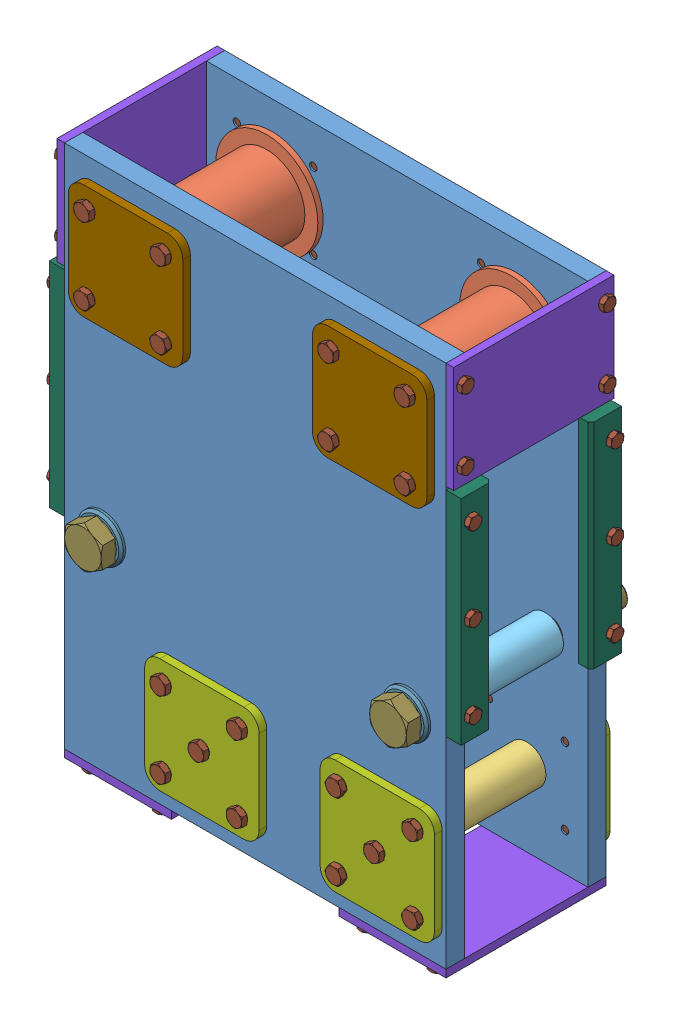
SolidWorks assembly 010200_trolley, configuration Default. Lengths in mm.
Overall size (277 352.5 150).
103 component instances, 15 part files, 231 mates.
Components (placement in the parent):
- 010201_trolley_main_plate-1: 010201_trolley_main_plate [Default] at (-125 -294 -52.5) size (250 344 12)
- 010201_trolley_main_plate-3: 010201_trolley_main_plate [Default] at (-125 -294 40.5) size (250 344 12)
- 010202_trolley_roller-1: 010202_trolley_roller [Default] at (-205 -50 0) size (67 67 105)
- 010202_trolley_roller-2: 010202_trolley_roller [Default] at (-45 -50 0) size (67 67 105)
- 010203_trolley_cylinder_pin-1: 010203_trolley_cylinder_pin [Default] at (-40 -294 0) size (25 25 105)
- 010203_trolley_cylinder_pin-3: 010203_trolley_cylinder_pin [Default] at (-155 -294 0) size (25 25 105)
- 010204_trolley_winch-1: 010204_trolley_winch [Default] at (-155 -294 0) x (0 0 1) z (0 1 0) size (30 100 100)
- 010205_trolley_small_roll-2: 010205_trolley_small_roll [Default] at (-25 -211 0) size (24 24 75)
- 010205_trolley_small_roll-3: 010205_trolley_small_roll [Default] at (-225 -211 0) size (24 24 75)
- 010207_trolley_distance_sleeve-2: 010207_trolley_distance_sleeve [Default] at (-155 -294 28) size (32 32 25)
- 010207_trolley_distance_sleeve-1: 010207_trolley_distance_sleeve [Default] at (-155 -294 -28) size (32 32 25)
- 010209_trolley_pincover-6: 010209_trolley_pincover [Default] at (-40 -294 -52.5) x (0 1 0) z (0 0 -1) size (75 75 5)
- 010209_trolley_pincover-7: 010209_trolley_pincover [Default] at (-155 -294 52.5) x (-1 0 0) z (0 0 1) size (75 75 5)
- 010209_trolley_pincover-8: 010209_trolley_pincover [Default] at (-155 -294 -52.5) x (1 0 0) z (0 0 -1) size (75 75 5)
- 010210_trolley_front_plate-4: 010210_trolley_front_plate [Default] at (-252.5 -35 0) x (0 0 1) z (-1 0 0) size (105 70 5)
- 010210_trolley_front_plate-8: 010210_trolley_front_plate [Default] at (2.5 -35 0) x (0 0 -1) z (1 0 0) size (105 70 5)
- 010210_trolley_front_plate-9: 010210_trolley_front_plate [Default] at (-35 -346.5 0) x (0 0 1) z (0 -1 0) size (105 70 5)
- 010210_trolley_front_plate-10: 010210_trolley_front_plate [Default] at (-215 -346.5 0) x (0 0 1) z (0 -1 0) size (105 70 5)
- 010208_trolley_bearing_cover-1: 010208_trolley_bearing_cover [Default] at (-205 -50 52.5) size (75 75 5)
- 010208_trolley_bearing_cover-7: 010208_trolley_bearing_cover [Default] at (-45 -50 52.5) size (75 75 5)
- 010208_trolley_bearing_cover-8: 010208_trolley_bearing_cover [Default] at (-45 -50 -52.5) x (-1 0 0) z (0 0 -1) size (75 75 5)
- 010208_trolley_bearing_cover-9: 010208_trolley_bearing_cover [Default] at (-205 -50 -52.5) x (-1 0 0) z (0 0 -1) size (75 75 5)
- SKF_6005_2z-1: SKF_6005_2z [Default] at (-45 -50 -52.5) size (47 47 12)
- SKF_6005_2z-2: SKF_6005_2z [Default] at (-205 -50 -52.5) size (47 47 12)
- SKF_6005_2z-3: SKF_6005_2z [Default] at (-205 -50 40.5) size (47 47 12)
- SKF_6005_2z-4: SKF_6005_2z [Default] at (-45 -50 40.5) size (47 47 12)
- 010209_trolley_pincover-9: 010209_trolley_pincover [Default] at (-40 -294 52.5) x (0 -1 0) z (0 0 1) size (75 75 5)
- hex screw gradeab_iso-78: hex screw gradeab_iso [ISO 4017 - M6 x 16-N] at (-40 -294 61.5) x (0 0 -1) z (1 0 0) size (20 11.55 10)
- hex screw gradeab_iso-79: hex screw gradeab_iso [ISO 4017 - M6 x 16-N] at (-155 -294 -61.5) x (0 0 1) z (-0.804894 -0.593418 0) size (20 11.55 10)
- hex screw gradeab_iso-80: hex screw gradeab_iso [ISO 4017 - M6 x 16-N] at (-40 -294 -61.5) x (0 0 1) z (-0.923728 -0.383049 0) size (20 11.55 10)
- hex screw gradeab_iso-81: hex screw gradeab_iso [ISO 4017 - M6 x 16-N] at (-155 -294 61.5) x (0 0 -1) z (1 0 0) size (20 11.55 10)
- hex bolt gradeab_iso-3: hex bolt gradeab_iso [ISO 4014 - M16 x 140 x 44-N] at (-225 -211 65.5) x (0 0 -1) z (1 0 0) size (150 27.71 24)
- hex nut style 1 gradeab_iso-1: hex nut style 1 gradeab_iso [ISO - 4032 - M16 - W - N] at (-225 -211 -70.3) x (-1 0 0) z (0 0 -1) size (24 27.71 14.8)
- hex nut style 1 gradeab_iso-4: hex nut style 1 gradeab_iso [ISO - 4032 - M16 - W - N] at (-25 -211 -70.3) x (-0.534174 -0.845375 0) z (0 0 -1) size (24 27.71 14.8)
- plain washer chamfered grade a_iso-7: plain washer chamfered grade a_iso [Washer ISO 7090 - 16] at (-25 -211 52.5) x (0 0 -1) z (0.534174 0.845375 0) size (3 30 30)
- plain washer chamfered grade a_iso-8: plain washer chamfered grade a_iso [Washer ISO 7090 - 16] at (-25 -211 -52.5) x (0 0 1) z (-1 0 0) size (3 30 30)
- hex bolt gradeab_iso-4: hex bolt gradeab_iso [ISO 4014 - M16 x 140 x 44-N] at (-25 -211 65.5) x (0 0 -1) z (0.534174 0.845375 0) size (150 27.71 24)
- plain washer chamfered grade a_iso-4: plain washer chamfered grade a_iso [Washer ISO 7090 - 16] at (-225 -211 52.5) x (0 0 -1) z (1 0 0) size (3 30 30)
- plain washer chamfered grade a_iso-6: plain washer chamfered grade a_iso [Washer ISO 7090 - 16] at (-225 -211 -52.5) x (0 0 1) z (-1 0 0) size (3 30 30)
- hex screw gradeab_iso-98: hex screw gradeab_iso [ISO 4017 - M5 x 16-N] at (13.5 -142 46.5) x (-1 0 0) z (0 0 -1) size (19.5 9.24 8)
- hex screw gradeab_iso-99: hex screw gradeab_iso [ISO 4017 - M5 x 16-N] at (13.5 -87 46.5) x (-1 0 0) z (0 0.461604 0.887086) size (19.5 9.24 8)
- hex screw gradeab_iso-100: hex screw gradeab_iso [ISO 4017 - M5 x 16-N] at (13.5 -197 46.5) x (-1 0 0) z (0 -0.924225 -0.381849) size (19.5 9.24 8)
- hex screw gradeab_iso-101: hex screw gradeab_iso [ISO 4017 - M5 x 16-N] at (-263.5 -87 -46.5) x (1 0 0) z (0 0.461604 -0.887086) size (19.5 9.24 8)
- hex screw gradeab_iso-102: hex screw gradeab_iso [ISO 4017 - M5 x 16-N] at (-263.5 -197 -46.5) x (1 0 0) z (0 -0.924225 0.381849) size (19.5 9.24 8)
- hex screw gradeab_iso-103: hex screw gradeab_iso [ISO 4017 - M5 x 16-N] at (-263.5 -142 -46.5) size (19.5 9.24 8)
- hex screw gradeab_iso-104: hex screw gradeab_iso [ISO 4017 - M5 x 16-N] at (-263.5 -197 46.5) x (1 0 0) z (0 -0.461604 0.887086) size (19.5 9.24 8)
- hex screw gradeab_iso-105: hex screw gradeab_iso [ISO 4017 - M5 x 16-N] at (-263.5 -87 46.5) x (1 0 0) z (0 0.924225 -0.381849) size (19.5 9.24 8)
- hex screw gradeab_iso-106: hex screw gradeab_iso [ISO 4017 - M5 x 16-N] at (-263.5 -142 46.5) x (1 0 0) z (0 0 -1) size (19.5 9.24 8)
- hex screw gradeab_iso-107: hex screw gradeab_iso [ISO 4017 - M5 x 16-N] at (13.5 -197 -46.5) x (-1 0 0) z (0 -0.461604 -0.887086) size (19.5 9.24 8)
- hex screw gradeab_iso-108: hex screw gradeab_iso [ISO 4017 - M5 x 16-N] at (13.5 -87 -46.5) x (-1 0 0) z (0 0.924225 0.381849) size (19.5 9.24 8)
- hex screw gradeab_iso-109: hex screw gradeab_iso [ISO 4017 - M5 x 16-N] at (13.5 -142 -46.5) x (-1 0 0) z (0 0 1) size (19.5 9.24 8)
- hex screw gradeab_iso-65: hex screw gradeab_iso [ISO 4017 - M6 x 16-N] at (-15 -319 -61.5) x (0 0 1) z (0 1 0) size (20 11.55 10)
- hex screw gradeab_iso-66: hex screw gradeab_iso [ISO 4017 - M6 x 16-N] at (-15 -269 -61.5) x (0 0 1) z (-0.923728 -0.383049 0) size (20 11.55 10)
- hex screw gradeab_iso-67: hex screw gradeab_iso [ISO 4017 - M6 x 16-N] at (-65 -269 -61.5) x (0 0 1) z (0 1 0) size (20 11.55 10)
- hex screw gradeab_iso-68: hex screw gradeab_iso [ISO 4017 - M6 x 16-N] at (-65 -319 -61.5) x (0 0 1) z (0 1 0) size (20 11.55 10)
- hex screw gradeab_iso-82: hex screw gradeab_iso [ISO 4017 - M5 x 16-N] at (-258.5 -12 46.5) x (1 0 0) z (0 0.924225 0.381849) size (19.5 9.24 8)
- hex screw gradeab_iso-83: hex screw gradeab_iso [ISO 4017 - M5 x 16-N] at (-258.5 -12 -46.5) size (19.5 9.24 8)
- hex screw gradeab_iso-84: hex screw gradeab_iso [ISO 4017 - M5 x 16-N] at (-258.5 -58 46.5) size (19.5 9.24 8)
- hex screw gradeab_iso-85: hex screw gradeab_iso [ISO 4017 - M5 x 16-N] at (-258.5 -58 -46.5) size (19.5 9.24 8)
- hex screw gradeab_iso-90: hex screw gradeab_iso [ISO 4017 - M5 x 16-N] at (8.5 -12 -46.5) x (-1 0 0) z (0 0.93115 -0.364637) size (19.5 9.24 8)
- hex screw gradeab_iso-91: hex screw gradeab_iso [ISO 4017 - M5 x 16-N] at (8.5 -12 46.5) x (-1 0 0) z (0 0 -1) size (19.5 9.24 8)
- hex screw gradeab_iso-92: hex screw gradeab_iso [ISO 4017 - M5 x 16-N] at (8.5 -58 -46.5) x (-1 0 0) z (0 0 -1) size (19.5 9.24 8)
- hex screw gradeab_iso-93: hex screw gradeab_iso [ISO 4017 - M5 x 16-N] at (8.5 -58 46.5) x (-1 0 0) z (0 0 -1) size (19.5 9.24 8)
- hex screw gradeab_iso-86: hex screw gradeab_iso [ISO 4017 - M5 x 16-N] at (-58 -352.5 46.5) x (0 1 0) z (-0.924225 0 0.381849) size (19.5 9.24 8)
- hex screw gradeab_iso-87: hex screw gradeab_iso [ISO 4017 - M5 x 16-N] at (-58 -352.5 -46.5) x (0 1 0) z (0 0 1) size (19.5 9.24 8)
- hex screw gradeab_iso-88: hex screw gradeab_iso [ISO 4017 - M5 x 16-N] at (-12 -352.5 46.5) x (0 1 0) z (0 0 1) size (19.5 9.24 8)
- hex screw gradeab_iso-89: hex screw gradeab_iso [ISO 4017 - M5 x 16-N] at (-12 -352.5 -46.5) x (0 1 0) z (0 0 1) size (19.5 9.24 8)
- hex screw gradeab_iso-94: hex screw gradeab_iso [ISO 4017 - M5 x 16-N] at (-238 -352.5 46.5) x (0 1 0) z (-0.924225 0 0.381849) size (19.5 9.24 8)
- hex screw gradeab_iso-95: hex screw gradeab_iso [ISO 4017 - M5 x 16-N] at (-238 -352.5 -46.5) x (0 1 0) z (0 0 1) size (19.5 9.24 8)
- hex screw gradeab_iso-96: hex screw gradeab_iso [ISO 4017 - M5 x 16-N] at (-192 -352.5 46.5) x (0 1 0) z (0 0 1) size (19.5 9.24 8)
- hex screw gradeab_iso-97: hex screw gradeab_iso [ISO 4017 - M5 x 16-N] at (-192 -352.5 -46.5) x (0 1 0) z (0 0 1) size (19.5 9.24 8)
- hex screw gradeab_iso-25: hex screw gradeab_iso [ISO 4017 - M6 x 16-N] at (-180 -25 61.5) x (0 0 -1) z (1 0 0) size (20 11.55 10)
- hex screw gradeab_iso-26: hex screw gradeab_iso [ISO 4017 - M6 x 16-N] at (-230 -25 61.5) x (0 0 -1) z (1 0 0) size (20 11.55 10)
- hex screw gradeab_iso-27: hex screw gradeab_iso [ISO 4017 - M6 x 16-N] at (-230 -75 61.5) x (0 0 -1) z (0.923728 0.383049 0) size (20 11.55 10)
- hex screw gradeab_iso-28: hex screw gradeab_iso [ISO 4017 - M6 x 16-N] at (-180 -75 61.5) x (0 0 -1) z (0.923728 0.383049 0) size (20 11.55 10)
- hex screw gradeab_iso-29: hex screw gradeab_iso [ISO 4017 - M6 x 16-N] at (-20 -25 61.5) x (0 0 -1) z (1 0 0) size (20 11.55 10)
- hex screw gradeab_iso-30: hex screw gradeab_iso [ISO 4017 - M6 x 16-N] at (-70 -25 61.5) x (0 0 -1) z (1 0 0) size (20 11.55 10)
- hex screw gradeab_iso-31: hex screw gradeab_iso [ISO 4017 - M6 x 16-N] at (-70 -75 61.5) x (0 0 -1) z (0.923728 0.383049 0) size (20 11.55 10)
- hex screw gradeab_iso-32: hex screw gradeab_iso [ISO 4017 - M6 x 16-N] at (-20 -75 61.5) x (0 0 -1) z (0.923728 0.383049 0) size (20 11.55 10)
- hex screw gradeab_iso-33: hex screw gradeab_iso [ISO 4017 - M6 x 16-N] at (-70 -25 -61.5) x (0 0 1) z (-1 0 0) size (20 11.55 10)
- hex screw gradeab_iso-34: hex screw gradeab_iso [ISO 4017 - M6 x 16-N] at (-20 -25 -61.5) x (0 0 1) z (0.544188 0.838963 0) size (20 11.55 10)
- hex screw gradeab_iso-35: hex screw gradeab_iso [ISO 4017 - M6 x 16-N] at (-20 -75 -61.5) x (0 0 1) z (-0.923728 0.383049 0) size (20 11.55 10)
- hex screw gradeab_iso-36: hex screw gradeab_iso [ISO 4017 - M6 x 16-N] at (-70 -75 -61.5) x (0 0 1) z (-0.923728 0.383049 0) size (20 11.55 10)
- hex screw gradeab_iso-37: hex screw gradeab_iso [ISO 4017 - M6 x 16-N] at (-230 -25 -61.5) x (0 0 1) z (-1 0 0) size (20 11.55 10)
- hex screw gradeab_iso-38: hex screw gradeab_iso [ISO 4017 - M6 x 16-N] at (-180 -25 -61.5) x (0 0 1) z (-0.088811 0.996049 0) size (20 11.55 10)
- hex screw gradeab_iso-39: hex screw gradeab_iso [ISO 4017 - M6 x 16-N] at (-180 -75 -61.5) x (0 0 1) z (-0.923728 0.383049 0) size (20 11.55 10)
- hex screw gradeab_iso-40: hex screw gradeab_iso [ISO 4017 - M6 x 16-N] at (-230 -75 -61.5) x (0 0 1) z (-0.923728 0.383049 0) size (20 11.55 10)
- hex screw gradeab_iso-62: hex screw gradeab_iso [ISO 4017 - M6 x 16-N] at (-15 -269 61.5) x (0 0 -1) z (1 0 0) size (20 11.55 10)
- hex screw gradeab_iso-61: hex screw gradeab_iso [ISO 4017 - M6 x 16-N] at (-15 -319 61.5) x (0 0 -1) z (0 -1 0) size (20 11.55 10)
- hex screw gradeab_iso-63: hex screw gradeab_iso [ISO 4017 - M6 x 16-N] at (-65 -319 61.5) x (0 0 -1) z (0 -1 0) size (20 11.55 10)
- hex screw gradeab_iso-64: hex screw gradeab_iso [ISO 4017 - M6 x 16-N] at (-65 -269 61.5) x (0 0 -1) z (0 -1 0) size (20 11.55 10)
- hex screw gradeab_iso-69: hex screw gradeab_iso [ISO 4017 - M6 x 16-N] at (-130 -319 61.5) x (0 0 -1) z (-1 0 0) size (20 11.55 10)
- hex screw gradeab_iso-70: hex screw gradeab_iso [ISO 4017 - M6 x 16-N] at (-180 -319 61.5) x (0 0 -1) z (-1 0 0) size (20 11.55 10)
- hex screw gradeab_iso-71: hex screw gradeab_iso [ISO 4017 - M6 x 16-N] at (-180 -269 61.5) x (0 0 -1) z (-1 0 0) size (20 11.55 10)
- hex screw gradeab_iso-72: hex screw gradeab_iso [ISO 4017 - M6 x 16-N] at (-130 -269 61.5) x (0 0 -1) z (-1 0 0) size (20 11.55 10)
- hex screw gradeab_iso-73: hex screw gradeab_iso [ISO 4017 - M6 x 16-N] at (-180 -319 -61.5) x (0 0 1) z (1 0 0) size (20 11.55 10)
- hex screw gradeab_iso-74: hex screw gradeab_iso [ISO 4017 - M6 x 16-N] at (-130 -319 -61.5) x (0 0 1) z (1 0 0) size (20 11.55 10)
- hex screw gradeab_iso-75: hex screw gradeab_iso [ISO 4017 - M6 x 16-N] at (-130 -269 -61.5) x (0 0 1) z (1 0 0) size (20 11.55 10)
- hex screw gradeab_iso-76: hex screw gradeab_iso [ISO 4017 - M6 x 16-N] at (-180 -269 -61.5) x (0 0 1) z (-0.677902 -0.735152 0) size (20 11.55 10)
- 010206_trolley_guide-1: 010206_trolley_guide [Default] at (0 -142 42.5) x (0 0 -1) z (1 0 0) size (20 140 10)
- 010206_trolley_guide-5: 010206_trolley_guide [Default] at (-250 -142 -42.5) x (0 0 1) z (-1 0 0) size (20 140 10)
- 010206_trolley_guide-6: 010206_trolley_guide [Default] at (-250 -142 42.5) x (0 0 -1) z (-1 0 0) size (20 140 10)
- 010206_trolley_guide-7: 010206_trolley_guide [Default] at (0 -142 -42.5) x (0 0 1) z (1 0 0) size (20 140 10)
Mates (geometry in assembly coordinates):
- Concentric1: concentric anti-aligned: cylinder of Trolley_main_plate-1 through (-45 -50 -40.5) axis (0 0 -1) radius 23.5; cylinder of 010202_trolley_roller-2 through (-45 -50 0) axis (0 0 1) radius 16
- Coincident1: coincident aligned: plane of Trolley_main_plate-1 through (-125 -294 -52.5) normal (0 0 -1); plane of 010202_trolley_roller-2 through (-45 -50 -52.5) normal (0 0 -1)
- Concentric2: concentric aligned: cylinder of Trolley_main_plate-1 through (-45 -50 -40.5) axis (0 0 -1) radius 23.5; cylinder of SKF_6005_2z-1 through (-45 -50 -40.5) axis (0 0 -1) radius 23.5
- Coincident2: coincident aligned: plane of Trolley_main_plate-1 through (-125 -294 -52.5) normal (0 0 -1); plane of SKF_6005_2z-1 through (-45 -50 -52.5) normal (0 0 -1)
- Concentric3: concentric aligned: cylinder of Trolley_main_plate-1 through (-205 -50 -40.5) axis (0 0 -1) radius 23.5; cylinder of SKF_6005_2z-2 through (-205 -50 -40.5) axis (0 0 -1) radius 12.5
- Coincident3: coincident aligned: plane of Trolley_main_plate-1 through (-125 -294 -52.5) normal (0 0 -1); plane of SKF_6005_2z-2 through (-205 -50 -52.5) normal (0 0 -1)
- Concentric4: concentric aligned: cylinder of 010202_trolley_roller-1 through (-205 -50 0) axis (0 0 1) radius 16; circle of SKF_6005_2z-2
- Coincident4: coincident aligned: plane of Trolley_main_plate-1 through (-125 -294 -52.5) normal (0 0 -1); plane of 010202_trolley_roller-1 through (-205 -50 -52.5) normal (0 0 -1)
- Concentric14: concentric aligned: cylinder of SKF_6005_2z-4 through (-45 -50 52.5) axis (0 0 -1) radius 23.5; cylinder of Trolley_main_plate-3 through (-45 -50 52.5) axis (0 0 -1) radius 23.5
- Concentric15: concentric aligned: cylinder of SKF_6005_2z-3 through (-205 -50 52.5) axis (0 0 -1) radius 12.5; cylinder of Trolley_main_plate-3 through (-205 -50 52.5) axis (0 0 -1) radius 23.5
- Coincident10: coincident aligned: plane of SKF_6005_2z-4 through (-45 -50 40.5) normal (0 0 -1); plane of Trolley_main_plate-3 through (-125 -294 40.5) normal (0 0 -1)
- Coincident11: coincident aligned: plane of SKF_6005_2z-3 through (-205 -50 40.5) normal (0 0 -1); plane of Trolley_main_plate-3 through (-125 -294 40.5) normal (0 0 -1)
- Concentric16: concentric anti-aligned: cylinder of 010202_trolley_roller-2 through (-45 -50 0) axis (0 0 1) radius 16; cylinder of SKF_6005_2z-4 through (-45 -50 52.5) axis (0 0 -1) radius 12.5
- Concentric17: concentric anti-aligned: cylinder of 010202_trolley_roller-1 through (-205 -50 0) axis (0 0 1) radius 16; cylinder of SKF_6005_2z-3 through (-205 -50 52.5) axis (0 0 -1) radius 12.5
- Coincident12: coincident aligned: plane of 010202_trolley_roller-1 through (-205 -50 52.5) normal (0 0 1); plane of Trolley_main_plate-3 through (-125 -294 52.5) normal (0 0 1)
- Coincident13: coincident aligned: plane of Trolley_main_plate-3 through (-125 -294 52.5) normal (0 0 1); plane of trolley_cylinder_pin-1 through (-40 -294 52.5) normal (0 0 1)
- Coincident14: coincident aligned: plane of 010202_trolley_roller-1 through (-205 -50 0) normal (0 0 1)
- Coincident15: coincident aligned: plane of Trolley_main_plate-1 through (-250 0 -40.5) normal (0 1 0)
- Coincident16: coincident aligned: plane of Trolley_main_plate-1 through (0 0 -40.5) normal (1 0 0)
- Concentric18: concentric aligned: cylinder of Trolley_main_plate-1 through (-40 -294 -40.5) axis (0 0 -1) radius 12.5; cylinder of trolley_cylinder_pin-1 through (-40 -294 52.5) axis (0 0 -1) radius 12.5
- Parallel1: parallel aligned: plane of Trolley_main_plate-1 through (-125 -294 -52.5) normal (0 0 -1); plane of trolley_cylinder_pin-1 through (-40 -294 -52.5) normal (0 0 -1)
- Coincident30: coincident aligned: plane of trolley_small_roll-2 through (-25 -211 0) normal (0 0 1)
- Coincident31: coincident aligned: plane of trolley_small_roll-3 through (-225 -211 0) normal (0 0 1)
- Coincident33: coincident aligned: plane of Trolley_main_plate-3 through (-125 -294 52.5) normal (0 0 1); plane of trolley_guide-1 through (10 -212 52.5) normal (0 0 1)
- Coincident34: coincident anti-aligned: plane of Trolley_main_plate-3 through (0 0 52.5) normal (1 0 0); plane of trolley_guide-1 through (0 -142 42.5) normal (-1 0 0)
- Concentric22: concentric anti-aligned: cylinder of Trolley_main_plate-3 through (-225 -211 52.5) axis (0 0 -1) radius 8.5; cylinder of hex bolt gradeab_iso-3 through (-225 -211 65.5) axis (0 0 1) radius 8
- Coincident48: coincident anti-aligned: plane of hex bolt gradeab_iso-3 through (-225 -197.1436 55.5) normal (0 0 -1); plane of plain washer chamfered grade a_iso-4 through (-225 -197.5 55.5) normal (0 0 1)
- Concentric23: concentric aligned: cylinder of hex bolt gradeab_iso-3 through (-225 -211 65.5) axis (0 0 1) radius 8; cylinder of plain washer chamfered grade a_iso-4 through (-225 -211 87.425) axis (0 0 1) radius 8.5
- Concentric24: concentric anti-aligned: cylinder of hex bolt gradeab_iso-3 through (-225 -211 65.5) axis (0 0 1) radius 8; cylinder of hex nut style 1 gradeab_iso-1 through (-225 -211 -55.5) axis (0 0 -1) radius 7
- Coincident49: coincident anti-aligned: plane of hex nut style 1 gradeab_iso-1 through (-225 -197.1436 -55.5) normal (0 0 1); plane of plain washer chamfered grade a_iso-6 through (-225 -197.5 -55.5) normal (0 0 -1)
- Coincident50: coincident anti-aligned: plane of Trolley_main_plate-3 through (-125 -294 52.5) normal (0 0 1); plane of plain washer chamfered grade a_iso-4 through (-225 -202.5 52.5) normal (0 0 -1)
- Coincident51: coincident anti-aligned: plane of hex nut style 1 gradeab_iso-4 through (-36.7139 -203.5983 -55.5) normal (0 0 1); plane of plain washer chamfered grade a_iso-8 through (-25 -197.5 -55.5) normal (0 0 -1)
- Concentric25: concentric aligned: cylinder of plain washer chamfered grade a_iso-7 through (-25 -211 87.425) axis (0 0 1) radius 8.5; cylinder of hex bolt gradeab_iso-4 through (-25 -211 65.5) axis (0 0 1) radius 8
- Coincident52: coincident anti-aligned: plane of plain washer chamfered grade a_iso-7 through (-36.4126 -203.7887 55.5) normal (0 0 1); plane of hex bolt gradeab_iso-4 through (-36.7139 -203.5983 55.5) normal (0 0 -1)
- Concentric26: concentric anti-aligned: cylinder of hex nut style 1 gradeab_iso-4 through (-25 -211 -55.5) axis (0 0 -1) radius 7; cylinder of hex bolt gradeab_iso-4 through (-25 -211 65.5) axis (0 0 1) radius 8
- Concentric27: concentric anti-aligned: cylinder of plain washer chamfered grade a_iso-8 through (-25 -211 -87.425) axis (0 0 -1) radius 8.5; cylinder of hex bolt gradeab_iso-4 through (-25 -211 65.5) axis (0 0 1) radius 8
- Concentric28: concentric aligned: cylinder of hex nut style 1 gradeab_iso-4 through (-25 -211 -55.5) axis (0 0 -1) radius 7; cylinder of plain washer chamfered grade a_iso-8 through (-25 -211 -87.425) axis (0 0 -1) radius 8.5
- Concentric29: concentric anti-aligned: cylinder of Trolley_main_plate-3 through (-25 -211 52.5) axis (0 0 -1) radius 8.5; cylinder of hex bolt gradeab_iso-4 through (-25 -211 65.5) axis (0 0 1) radius 8
- Coincident53: coincident anti-aligned: plane of Trolley_main_plate-3 through (-125 -294 52.5) normal (0 0 1); plane of plain washer chamfered grade a_iso-7 through (-32.1857 -206.4595 52.5) normal (0 0 -1)
- Coincident54: coincident anti-aligned: plane of Trolley_main_plate-1 through (-125 -294 -52.5) normal (0 0 -1); plane of plain washer chamfered grade a_iso-8 through (-25 -202.5 -52.5) normal (0 0 1)
- Coincident55: coincident anti-aligned: plane of Trolley_main_plate-1 through (-125 -294 -52.5) normal (0 0 -1); plane of plain washer chamfered grade a_iso-6 through (-225 -202.5 -52.5) normal (0 0 1)
- Concentric31: concentric anti-aligned: cylinder of hex bolt gradeab_iso-3 through (-225 -211 65.5) axis (0 0 1) radius 8; cylinder of plain washer chamfered grade a_iso-6 through (-225 -211 -87.425) axis (0 0 -1) radius 8.5
- Concentric37: concentric anti-aligned: cylinder of trolley_small_roll-2 through (-25 -211 37.5) axis (0 0 -1) radius 8.5; cylinder of hex bolt gradeab_iso-4 through (-25 -211 65.5) axis (0 0 1) radius 8
- Concentric38: concentric anti-aligned: cylinder of trolley_small_roll-3 through (-225 -211 37.5) axis (0 0 -1) radius 12; cylinder of hex bolt gradeab_iso-3 through (-225 -211 65.5) axis (0 0 1) radius 8
- Coincident64: coincident aligned: plane of Trolley_main_plate-1 through (-125 -294 -52.5) normal (0 0 -1); plane of trolley_front_plate-4 through (-255 0 -52.5) normal (0 0 -1)
- Coincident65: coincident anti-aligned: plane of Trolley_main_plate-1 through (-250 -344 -40.5) normal (-1 0 0); plane of trolley_front_plate-4 through (-250 -35 0) normal (1 0 0)
- Coincident66: coincident aligned: plane of Trolley_main_plate-1 through (-250 0 -40.5) normal (0 1 0); plane of trolley_front_plate-4 through (-255 0 -52.5) normal (0 1 0)
- Concentric39: concentric aligned: cylinder of Trolley_main_plate-3 through (-230 -25 52.5) axis (0 0 1) radius 2.5; cylinder of trolley_bearingcover-1 through (-230 -25 57.5) axis (0 0 1) radius 3.5
- Concentric40: concentric aligned: cylinder of Trolley_main_plate-3 through (-180 -25 52.5) axis (0 0 1) radius 2.5; cylinder of trolley_bearingcover-1 through (-180 -25 57.5) axis (0 0 1) radius 3.5
- Coincident67: coincident anti-aligned: plane of Trolley_main_plate-3 through (-125 -294 52.5) normal (0 0 1); plane of trolley_bearingcover-1 through (-205 -50 52.5) normal (0 0 -1)
- Coincident102: coincident aligned: plane of trolley_winch-1 through (-155 -294 0) normal (0 0 1)
- Parallel2: parallel anti-aligned: plane of Trolley_main_plate-1 through (-250 -344 -40.5) normal (-1 0 0); plane of trolley_winch-1 through (-115 -294 0) normal (1 0 0)
- Concentric91: concentric aligned: cylinder of trolley_bearingcover-1 through (-230 -25 57.5) axis (0 0 1) radius 3.5; cylinder of hex screw gradeab_iso-26 through (-230 -25 61.5) axis (0 0 1) radius 3
- Concentric92: concentric aligned: cylinder of trolley_bearingcover-1 through (-180 -25 57.5) axis (0 0 1) radius 3.5; cylinder of hex screw gradeab_iso-25 through (-180 -25 61.5) axis (0 0 1) radius 3
- Concentric93: concentric aligned: cylinder of trolley_bearingcover-1 through (-230 -75 57.5) axis (0 0 1) radius 3.5; cylinder of hex screw gradeab_iso-27 through (-230 -75 61.5) axis (0 0 1) radius 3
- Concentric94: concentric aligned: cylinder of trolley_bearingcover-1 through (-180 -75 57.5) axis (0 0 1) radius 3.5; cylinder of hex screw gradeab_iso-28 through (-180 -75 61.5) axis (0 0 1) radius 3
- Coincident109: coincident anti-aligned: plane of trolley_bearingcover-1 through (-205 -50 57.5) normal (0 0 1); plane of hex screw gradeab_iso-26 through (-230 -19.2265 57.5) normal (0 0 -1)
- Coincident110: coincident anti-aligned: plane of trolley_bearingcover-1 through (-205 -50 57.5) normal (0 0 1); plane of hex screw gradeab_iso-28 through (-182.2115 -69.6669 57.5) normal (0 0 -1)
- Coincident111: coincident anti-aligned: plane of trolley_bearingcover-1 through (-205 -50 57.5) normal (0 0 1); plane of hex screw gradeab_iso-27 through (-232.2115 -69.6669 57.5) normal (0 0 -1)
- Coincident112: coincident anti-aligned: plane of trolley_bearingcover-1 through (-205 -50 57.5) normal (0 0 1); plane of hex screw gradeab_iso-25 through (-180 -19.2265 57.5) normal (0 0 -1)
- Concentric95: concentric aligned: cylinder of hex screw gradeab_iso-30 through (-70 -25 61.5) axis (0 0 1) radius 3; cylinder of trolley_bearingcover-7 through (-70 -25 57.5) axis (0 0 1) radius 3.5
- Concentric96: concentric aligned: cylinder of hex screw gradeab_iso-31 through (-70 -75 61.5) axis (0 0 1) radius 3; cylinder of trolley_bearingcover-7 through (-70 -75 57.5) axis (0 0 1) radius 3.5
- Concentric97: concentric aligned: cylinder of hex screw gradeab_iso-29 through (-20 -25 61.5) axis (0 0 1) radius 3; cylinder of trolley_bearingcover-7 through (-20 -25 57.5) axis (0 0 1) radius 3.5
- Concentric98: concentric aligned: cylinder of hex screw gradeab_iso-32 through (-20 -75 61.5) axis (0 0 1) radius 3; cylinder of trolley_bearingcover-7 through (-20 -75 57.5) axis (0 0 1) radius 3.5
- Coincident113: coincident anti-aligned: plane of hex screw gradeab_iso-30 through (-70 -19.2265 57.5) normal (0 0 -1); plane of trolley_bearingcover-7 through (-45 -50 57.5) normal (0 0 1)
- Coincident114: coincident anti-aligned: plane of hex screw gradeab_iso-32 through (-22.2115 -69.6669 57.5) normal (0 0 -1); plane of trolley_bearingcover-7 through (-45 -50 57.5) normal (0 0 1)
- Coincident115: coincident anti-aligned: plane of hex screw gradeab_iso-31 through (-72.2115 -69.6669 57.5) normal (0 0 -1); plane of trolley_bearingcover-7 through (-45 -50 57.5) normal (0 0 1)
- Coincident116: coincident anti-aligned: plane of hex screw gradeab_iso-29 through (-20 -19.2265 57.5) normal (0 0 -1); plane of trolley_bearingcover-7 through (-45 -50 57.5) normal (0 0 1)
- Concentric99: concentric aligned: cylinder of hex screw gradeab_iso-34 through (-20 -25 -61.5) axis (0 0 -1) radius 3; cylinder of trolley_bearingcover-8 through (-20 -25 -57.5) axis (0 0 -1) radius 3.5
- Concentric100: concentric aligned: cylinder of hex screw gradeab_iso-35 through (-20 -75 -61.5) axis (0 0 -1) radius 3; cylinder of trolley_bearingcover-8 through (-20 -75 -57.5) axis (0 0 -1) radius 3.5
- Concentric101: concentric aligned: cylinder of hex screw gradeab_iso-33 through (-70 -25 -61.5) axis (0 0 -1) radius 3; cylinder of trolley_bearingcover-8 through (-70 -25 -57.5) axis (0 0 -1) radius 3.5
- Concentric102: concentric aligned: cylinder of hex screw gradeab_iso-36 through (-70 -75 -61.5) axis (0 0 -1) radius 3; cylinder of trolley_bearingcover-8 through (-70 -75 -57.5) axis (0 0 -1) radius 3.5
- Coincident117: coincident anti-aligned: plane of hex screw gradeab_iso-34 through (-15.1562 -28.1419 -57.5) normal (0 0 1); plane of trolley_bearingcover-8 through (-45 -50 -57.5) normal (0 0 -1)
- Coincident118: coincident anti-aligned: plane of hex screw gradeab_iso-36 through (-67.7885 -69.6669 -57.5) normal (0 0 1); plane of trolley_bearingcover-8 through (-45 -50 -57.5) normal (0 0 -1)
- Coincident119: coincident anti-aligned: plane of hex screw gradeab_iso-35 through (-17.7885 -69.6669 -57.5) normal (0 0 1); plane of trolley_bearingcover-8 through (-45 -50 -57.5) normal (0 0 -1)
- Coincident120: coincident anti-aligned: plane of hex screw gradeab_iso-33 through (-70 -19.2265 -57.5) normal (0 0 1); plane of trolley_bearingcover-8 through (-45 -50 -57.5) normal (0 0 -1)
- Concentric103: concentric aligned: cylinder of hex screw gradeab_iso-38 through (-180 -25 -61.5) axis (0 0 -1) radius 3; cylinder of trolley_bearingcover-9 through (-180 -25 -57.5) axis (0 0 -1) radius 3.5
- Concentric104: concentric aligned: cylinder of hex screw gradeab_iso-39 through (-180 -75 -61.5) axis (0 0 -1) radius 3; cylinder of trolley_bearingcover-9 through (-180 -75 -57.5) axis (0 0 -1) radius 3.5
- Concentric105: concentric aligned: cylinder of hex screw gradeab_iso-37 through (-230 -25 -61.5) axis (0 0 -1) radius 3; cylinder of trolley_bearingcover-9 through (-230 -25 -57.5) axis (0 0 -1) radius 3.5
- Concentric106: concentric aligned: cylinder of hex screw gradeab_iso-40 through (-230 -75 -61.5) axis (0 0 -1) radius 3; cylinder of trolley_bearingcover-9 through (-230 -75 -57.5) axis (0 0 -1) radius 3.5
- Coincident121: coincident anti-aligned: plane of hex screw gradeab_iso-38 through (-174.2493 -24.4873 -57.5) normal (0 0 1); plane of trolley_bearingcover-9 through (-205 -50 -57.5) normal (0 0 -1)
- Coincident122: coincident anti-aligned: plane of hex screw gradeab_iso-40 through (-227.7885 -69.6669 -57.5) normal (0 0 1); plane of trolley_bearingcover-9 through (-205 -50 -57.5) normal (0 0 -1)
- Coincident123: coincident anti-aligned: plane of hex screw gradeab_iso-39 through (-177.7885 -69.6669 -57.5) normal (0 0 1); plane of trolley_bearingcover-9 through (-205 -50 -57.5) normal (0 0 -1)
- Coincident124: coincident anti-aligned: plane of hex screw gradeab_iso-37 through (-230 -19.2265 -57.5) normal (0 0 1); plane of trolley_bearingcover-9 through (-205 -50 -57.5) normal (0 0 -1)
- Coincident145: coincident anti-aligned: plane of Trolley_main_plate-3 through (-125 -294 52.5) normal (0 0 1); plane of trolley_bearingcover-7 through (-45 -50 52.5) normal (0 0 -1)
- Concentric127: concentric aligned: cylinder of Trolley_main_plate-3 through (-70 -25 52.5) axis (0 0 1) radius 2.5; cylinder of hex screw gradeab_iso-30 through (-70 -25 61.5) axis (0 0 1) radius 3
- Concentric128: concentric aligned: cylinder of Trolley_main_plate-3 through (-20 -75 52.5) axis (0 0 1) radius 2.5; cylinder of hex screw gradeab_iso-32 through (-20 -75 61.5) axis (0 0 1) radius 3
- Coincident146: coincident anti-aligned: plane of Trolley_main_plate-1 through (-125 -294 -52.5) normal (0 0 -1); plane of trolley_bearingcover-8 through (-45 -50 -52.5) normal (0 0 1)
- Coincident147: coincident anti-aligned: plane of Trolley_main_plate-1 through (-125 -294 -52.5) normal (0 0 -1); plane of trolley_bearingcover-9 through (-205 -50 -52.5) normal (0 0 1)
- Concentric129: concentric anti-aligned: cylinder of Trolley_main_plate-1 through (-20 -25 -40.5) axis (0 0 1) radius 2.5; cylinder of hex screw gradeab_iso-34 through (-20 -25 -61.5) axis (0 0 -1) radius 3
- Concentric130: concentric anti-aligned: circle of Trolley_main_plate-1; cylinder of hex screw gradeab_iso-38 through (-180 -25 -61.5) axis (0 0 -1) radius 3
- Concentric133: concentric anti-aligned: cylinder of Trolley_main_plate-1 through (-230 -75 -40.5) axis (0 0 1) radius 2.5; cylinder of hex screw gradeab_iso-40 through (-230 -75 -61.5) axis (0 0 -1) radius 3
- Concentric134: concentric anti-aligned: cylinder of Trolley_main_plate-1 through (-70 -75 -40.5) axis (0 0 1) radius 2.5; cylinder of hex screw gradeab_iso-36 through (-70 -75 -61.5) axis (0 0 -1) radius 3
- Concentric135: concentric aligned: cylinder of hex screw gradeab_iso-61 through (-15 -319 61.5) axis (0 0 1) radius 3; cylinder of trolley_pincover-5 through (-15 -319 57.5) axis (0 0 1) radius 3.5
- Concentric136: concentric aligned: circle of trolley_pincover-5; cylinder of hex screw gradeab_iso-62 through (-15 -269 61.5) axis (0 0 1) radius 3
- Concentric137: concentric aligned: cylinder of trolley_pincover-5 through (-65 -319 57.5) axis (0 0 1) radius 3.5; cylinder of hex screw gradeab_iso-63 through (-65 -319 61.5) axis (0 0 1) radius 3
- Concentric138: concentric aligned: cylinder of trolley_pincover-5 through (-65 -269 57.5) axis (0 0 1) radius 3.5; cylinder of hex screw gradeab_iso-64 through (-65 -269 61.5) axis (0 0 1) radius 3
- Coincident148: coincident anti-aligned: plane of hex screw gradeab_iso-61 through (-9.2265 -319 57.5) normal (0 0 -1); plane of trolley_pincover-5 through (-40 -294 57.5) normal (0 0 1)
- Coincident149: coincident anti-aligned: plane of trolley_pincover-5 through (-40 -294 57.5) normal (0 0 1); plane of hex screw gradeab_iso-62 through (-15 -263.2265 57.5) normal (0 0 -1)
- Coincident150: coincident anti-aligned: plane of trolley_pincover-5 through (-40 -294 57.5) normal (0 0 1); plane of hex screw gradeab_iso-63 through (-59.2265 -319 57.5) normal (0 0 -1)
- Coincident151: coincident anti-aligned: plane of trolley_pincover-5 through (-40 -294 57.5) normal (0 0 1); plane of hex screw gradeab_iso-64 through (-59.2265 -269 57.5) normal (0 0 -1)
- Coincident152: coincident anti-aligned: plane of hex screw gradeab_iso-66 through (-17.2115 -263.6669 -57.5) normal (0 0 1); plane of trolley_pincover-6 through (-40 -294 -57.5) normal (0 0 -1)
- Concentric139: concentric aligned: cylinder of hex screw gradeab_iso-68 through (-65 -319 -61.5) axis (0 0 -1) radius 3; cylinder of trolley_pincover-6 through (-65 -319 -57.5) axis (0 0 -1) radius 3.5
- Coincident153: coincident anti-aligned: plane of hex screw gradeab_iso-65 through (-9.2265 -319 -57.5) normal (0 0 1); plane of trolley_pincover-6 through (-40 -294 -57.5) normal (0 0 -1)
- Coincident154: coincident anti-aligned: plane of hex screw gradeab_iso-68 through (-59.2265 -319 -57.5) normal (0 0 1); plane of trolley_pincover-6 through (-40 -294 -57.5) normal (0 0 -1)
- Concentric140: concentric aligned: cylinder of hex screw gradeab_iso-66 through (-15 -269 -61.5) axis (0 0 -1) radius 3; cylinder of trolley_pincover-6 through (-15 -269 -57.5) axis (0 0 -1) radius 3.5
- Concentric141: concentric aligned: cylinder of hex screw gradeab_iso-67 through (-65 -269 -61.5) axis (0 0 -1) radius 3; cylinder of trolley_pincover-6 through (-65 -269 -57.5) axis (0 0 -1) radius 3.5
- Concentric142: concentric aligned: cylinder of hex screw gradeab_iso-65 through (-15 -319 -61.5) axis (0 0 -1) radius 3; circle of trolley_pincover-6
- Coincident155: coincident anti-aligned: plane of hex screw gradeab_iso-67 through (-59.2265 -269 -57.5) normal (0 0 1); plane of trolley_pincover-6 through (-40 -294 -57.5) normal (0 0 -1)
- Coincident156: coincident anti-aligned: plane of hex screw gradeab_iso-70 through (-180 -324.7735 57.5) normal (0 0 -1); plane of trolley_pincover-7 through (-155 -294 57.5) normal (0 0 1)
- Concentric143: concentric aligned: cylinder of hex screw gradeab_iso-72 through (-130 -269 61.5) axis (0 0 1) radius 3; cylinder of trolley_pincover-7 through (-130 -269 57.5) axis (0 0 1) radius 3.5
- Coincident157: coincident anti-aligned: plane of hex screw gradeab_iso-69 through (-130 -324.7735 57.5) normal (0 0 -1); plane of trolley_pincover-7 through (-155 -294 57.5) normal (0 0 1)
- Coincident158: coincident anti-aligned: plane of hex screw gradeab_iso-72 through (-130 -274.7735 57.5) normal (0 0 -1); plane of trolley_pincover-7 through (-155 -294 57.5) normal (0 0 1)
- Concentric144: concentric aligned: cylinder of hex screw gradeab_iso-70 through (-180 -319 61.5) axis (0 0 1) radius 3; cylinder of trolley_pincover-7 through (-180 -319 57.5) axis (0 0 1) radius 3.5
- Concentric145: concentric aligned: cylinder of hex screw gradeab_iso-71 through (-180 -269 61.5) axis (0 0 1) radius 3; cylinder of trolley_pincover-7 through (-180 -269 57.5) axis (0 0 1) radius 3.5
- Concentric146: concentric aligned: cylinder of hex screw gradeab_iso-69 through (-130 -319 61.5) axis (0 0 1) radius 3; circle of trolley_pincover-7
- Coincident159: coincident anti-aligned: plane of hex screw gradeab_iso-71 through (-180 -274.7735 57.5) normal (0 0 -1); plane of trolley_pincover-7 through (-155 -294 57.5) normal (0 0 1)
- Coincident160: coincident anti-aligned: plane of hex screw gradeab_iso-74 through (-130 -324.7735 -57.5) normal (0 0 1); plane of trolley_pincover-8 through (-155 -294 -57.5) normal (0 0 -1)
- Concentric147: concentric aligned: cylinder of hex screw gradeab_iso-76 through (-180 -269 -61.5) axis (0 0 -1) radius 3; cylinder of trolley_pincover-8 through (-180 -269 -57.5) axis (0 0 -1) radius 3.5
- Coincident161: coincident anti-aligned: plane of hex screw gradeab_iso-73 through (-180 -324.7735 -57.5) normal (0 0 1); plane of trolley_pincover-8 through (-155 -294 -57.5) normal (0 0 -1)
- Coincident162: coincident anti-aligned: plane of hex screw gradeab_iso-76 through (-184.2444 -265.0861 -57.5) normal (0 0 1); plane of trolley_pincover-8 through (-155 -294 -57.5) normal (0 0 -1)
- Concentric148: concentric aligned: cylinder of hex screw gradeab_iso-74 through (-130 -319 -61.5) axis (0 0 -1) radius 3; cylinder of trolley_pincover-8 through (-130 -319 -57.5) axis (0 0 -1) radius 3.5
- Concentric149: concentric aligned: cylinder of hex screw gradeab_iso-75 through (-130 -269 -61.5) axis (0 0 -1) radius 3; cylinder of trolley_pincover-8 through (-130 -269 -57.5) axis (0 0 -1) radius 3.5
- Concentric150: concentric aligned: cylinder of hex screw gradeab_iso-73 through (-180 -319 -61.5) axis (0 0 -1) radius 3; circle of trolley_pincover-8
- Coincident163: coincident anti-aligned: plane of hex screw gradeab_iso-75 through (-130 -274.7735 -57.5) normal (0 0 1); plane of trolley_pincover-8 through (-155 -294 -57.5) normal (0 0 -1)
- Coincident164: coincident anti-aligned: plane of Trolley_main_plate-3 through (-125 -294 52.5) normal (0 0 1); plane of trolley_pincover-5 through (-40 -294 52.5) normal (0 0 -1)
- Coincident165: coincident anti-aligned: plane of Trolley_main_plate-3 through (-125 -294 52.5) normal (0 0 1); plane of trolley_pincover-7 through (-155 -294 52.5) normal (0 0 -1)
- Coincident166: coincident anti-aligned: plane of Trolley_main_plate-1 through (-125 -294 -52.5) normal (0 0 -1); plane of trolley_pincover-8 through (-155 -294 -52.5) normal (0 0 1)
- Coincident167: coincident anti-aligned: plane of Trolley_main_plate-1 through (-125 -294 -52.5) normal (0 0 -1); plane of trolley_pincover-6 through (-40 -294 -52.5) normal (0 0 1)
- Concentric151: concentric anti-aligned: cylinder of Trolley_main_plate-1 through (-15 -269 -40.5) axis (0 0 1) radius 2.5; cylinder of hex screw gradeab_iso-66 through (-15 -269 -61.5) axis (0 0 -1) radius 3
- Concentric152: concentric anti-aligned: circle of Trolley_main_plate-1; cylinder of hex screw gradeab_iso-76 through (-180 -269 -61.5) axis (0 0 -1) radius 3
- Concentric153: concentric aligned: circle of Trolley_main_plate-3; cylinder of hex screw gradeab_iso-62 through (-15 -269 61.5) axis (0 0 1) radius 3
- Concentric154: concentric aligned: circle of Trolley_main_plate-3; cylinder of hex screw gradeab_iso-69 through (-130 -319 61.5) axis (0 0 1) radius 3
- Concentric155: concentric aligned: cylinder of Trolley_main_plate-3 through (-180 -269 52.5) axis (0 0 1) radius 2.5; cylinder of hex screw gradeab_iso-71 through (-180 -269 61.5) axis (0 0 1) radius 3
- Concentric157: concentric aligned: cylinder of Trolley_main_plate-3 through (-65 -319 52.5) axis (0 0 1) radius 2.5; cylinder of hex screw gradeab_iso-63 through (-65 -319 61.5) axis (0 0 1) radius 3
- Concentric158: concentric anti-aligned: cylinder of Trolley_main_plate-1 through (-65 -319 -40.5) axis (0 0 1) radius 2.5; cylinder of hex screw gradeab_iso-68 through (-65 -319 -61.5) axis (0 0 -1) radius 3
- Concentric159: concentric anti-aligned: cylinder of Trolley_main_plate-1 through (-130 -319 -40.5) axis (0 0 1) radius 2.5; cylinder of hex screw gradeab_iso-74 through (-130 -319 -61.5) axis (0 0 -1) radius 3
- Concentric160: concentric aligned: cylinder of Trolley_main_plate-3 through (-155 -294 52.5) axis (0 0 -1) radius 12.5; cylinder of trolley_cylinder_pin-3 through (-155 -294 52.5) axis (0 0 -1) radius 12.5
- Coincident168: coincident aligned: plane of Trolley_main_plate-1 through (-125 -294 -52.5) normal (0 0 -1); plane of trolley_cylinder_pin-3 through (-155 -294 -52.5) normal (0 0 -1)
- Concentric161: concentric aligned: cylinder of trolley_winch-1 through (-155 -294 -75.8883) axis (0 0 -1) radius 12.5; cylinder of trolley_cylinder_pin-3 through (-155 -294 52.5) axis (0 0 -1) radius 12.5
- Concentric163: concentric aligned: cylinder of trolley_pincover-7 through (-155 -294 57.5) axis (0 0 1) radius 3.5; cylinder of hex screw gradeab_iso-81 through (-155 -294 61.5) axis (0 0 1) radius 3
- Concentric164: concentric aligned: cylinder of trolley_pincover-5 through (-40 -294 57.5) axis (0 0 1) radius 3.5; cylinder of hex screw gradeab_iso-78 through (-40 -294 61.5) axis (0 0 1) radius 3
- Concentric166: concentric aligned: cylinder of trolley_pincover-8 through (-155 -294 -57.5) axis (0 0 -1) radius 3.5; cylinder of hex screw gradeab_iso-79 through (-155 -294 -61.5) axis (0 0 -1) radius 3
- Concentric167: concentric aligned: circle of trolley_pincover-6; cylinder of hex screw gradeab_iso-80 through (-40 -294 -61.5) axis (0 0 -1) radius 3
- Coincident169: coincident anti-aligned: plane of trolley_pincover-6 through (-40 -294 -57.5) normal (0 0 -1); plane of hex screw gradeab_iso-80 through (-42.2115 -288.6669 -57.5) normal (0 0 1)
- Coincident171: coincident anti-aligned: plane of trolley_pincover-8 through (-155 -294 -57.5) normal (0 0 -1); plane of hex screw gradeab_iso-79 through (-158.4261 -289.3529 -57.5) normal (0 0 1)
- Coincident172: coincident anti-aligned: plane of trolley_pincover-7 through (-155 -294 57.5) normal (0 0 1); plane of hex screw gradeab_iso-81 through (-155 -288.2265 57.5) normal (0 0 -1)
- Coincident173: coincident anti-aligned: plane of trolley_pincover-5 through (-40 -294 57.5) normal (0 0 1); plane of hex screw gradeab_iso-78 through (-40 -288.2265 57.5) normal (0 0 -1)
- Concentric168: concentric aligned: cylinder of trolley_cylinder_pin-3 through (-155 -294 52.5) axis (0 0 -1) radius 12.5; cylinder of trolley_distance_sleeve-1 through (-155 -294 -15.5) axis (0 0 -1) radius 12.5
- Concentric169: concentric aligned: cylinder of trolley_cylinder_pin-3 through (-155 -294 52.5) axis (0 0 -1) radius 12.5; cylinder of trolley_distance_sleeve-2 through (-155 -294 40.5) axis (0 0 -1) radius 12.5
- Coincident174: coincident anti-aligned: plane of Trolley_main_plate-1 through (-125 -294 -40.5) normal (0 0 1); plane of trolley_distance_sleeve-1 through (-155 -294 -40.5) normal (0 0 -1)
- Coincident175: coincident anti-aligned: plane of Trolley_main_plate-3 through (-125 -294 40.5) normal (0 0 -1); plane of trolley_distance_sleeve-2 through (-155 -294 40.5) normal (0 0 1)
- Concentric174: concentric aligned: cylinder of trolley_front_plate-4 through (-255 -12 -46.5) axis (-1 0 0) radius 3; cylinder of hex screw gradeab_iso-83 through (-258.5 -12 -46.5) axis (-1 0 0) radius 2.5
- Concentric175: concentric aligned: cylinder of trolley_front_plate-4 through (-255 -12 46.5) axis (-1 0 0) radius 3; cylinder of hex screw gradeab_iso-82 through (-258.5 -12 46.5) axis (-1 0 0) radius 2.5
- Concentric176: concentric aligned: cylinder of trolley_front_plate-4 through (-255 -58 -46.5) axis (-1 0 0) radius 3; cylinder of hex screw gradeab_iso-85 through (-258.5 -58 -46.5) axis (-1 0 0) radius 2.5
- Concentric177: concentric aligned: cylinder of trolley_front_plate-4 through (-255 -58 46.5) axis (-1 0 0) radius 3; cylinder of hex screw gradeab_iso-84 through (-258.5 -58 46.5) axis (-1 0 0) radius 2.5
- Coincident178: coincident anti-aligned: plane of trolley_front_plate-4 through (-255 -35 0) normal (-1 0 0); plane of hex screw gradeab_iso-85 through (-255 -53.3812 -46.5) normal (1 0 0)
- Coincident179: coincident anti-aligned: plane of trolley_front_plate-4 through (-255 -35 0) normal (-1 0 0); plane of hex screw gradeab_iso-83 through (-255 -7.3812 -46.5) normal (1 0 0)
- Coincident180: coincident anti-aligned: plane of trolley_front_plate-4 through (-255 -35 0) normal (-1 0 0); plane of hex screw gradeab_iso-84 through (-255 -53.3812 46.5) normal (1 0 0)
- Coincident181: coincident anti-aligned: plane of trolley_front_plate-4 through (-255 -35 0) normal (-1 0 0); plane of hex screw gradeab_iso-82 through (-255 -10.2363 42.2312) normal (1 0 0)
- Concentric178: concentric aligned: cylinder of hex screw gradeab_iso-86 through (-58 -352.5 46.5) axis (0 -1 0) radius 2.5; cylinder of trolley_front_plate-7 through (-58 -349 46.5) axis (0 -1 0) radius 3
- Coincident182: coincident anti-aligned: plane of hex screw gradeab_iso-89 through (-16.6188 -349 -46.5) normal (0 1 0); plane of trolley_front_plate-7 through (-35 -349 0) normal (0 -1 0)
- Concentric179: concentric aligned: cylinder of hex screw gradeab_iso-89 through (-12 -352.5 -46.5) axis (0 -1 0) radius 2.5; cylinder of trolley_front_plate-7 through (-12 -349 -46.5) axis (0 -1 0) radius 3
- Concentric180: concentric aligned: cylinder of hex screw gradeab_iso-88 through (-12 -352.5 46.5) axis (0 -1 0) radius 2.5; cylinder of trolley_front_plate-7 through (-12 -349 46.5) axis (0 -1 0) radius 3
- Coincident183: coincident anti-aligned: plane of hex screw gradeab_iso-88 through (-16.6188 -349 46.5) normal (0 1 0); plane of trolley_front_plate-7 through (-35 -349 0) normal (0 -1 0)
- Coincident184: coincident anti-aligned: plane of hex screw gradeab_iso-86 through (-59.7637 -349 42.2312) normal (0 1 0); plane of trolley_front_plate-7 through (-35 -349 0) normal (0 -1 0)
- Coincident185: coincident anti-aligned: plane of hex screw gradeab_iso-87 through (-62.6188 -349 -46.5) normal (0 1 0); plane of trolley_front_plate-7 through (-35 -349 0) normal (0 -1 0)
- Concentric181: concentric aligned: cylinder of hex screw gradeab_iso-87 through (-58 -352.5 -46.5) axis (0 -1 0) radius 2.5; cylinder of trolley_front_plate-7 through (-58 -349 -46.5) axis (0 -1 0) radius 3
- Concentric182: concentric aligned: cylinder of hex screw gradeab_iso-90 through (8.5 -12 -46.5) axis (1 0 0) radius 2.5; cylinder of trolley_front_plate-8 through (5 -12 -46.5) axis (1 0 0) radius 3
- Coincident186: coincident anti-aligned: plane of hex screw gradeab_iso-93 through (5 -53.3812 46.5) normal (-1 0 0); plane of trolley_front_plate-8 through (5 -35 0) normal (1 0 0)
- Concentric183: concentric aligned: cylinder of hex screw gradeab_iso-93 through (8.5 -58 46.5) axis (1 0 0) radius 2.5; cylinder of trolley_front_plate-8 through (5 -58 46.5) axis (1 0 0) radius 3
- Concentric184: concentric aligned: cylinder of hex screw gradeab_iso-92 through (8.5 -58 -46.5) axis (1 0 0) radius 2.5; cylinder of trolley_front_plate-8 through (5 -58 -46.5) axis (1 0 0) radius 3
- Coincident187: coincident anti-aligned: plane of hex screw gradeab_iso-92 through (5 -53.3812 -46.5) normal (-1 0 0); plane of trolley_front_plate-8 through (5 -35 0) normal (1 0 0)
- Coincident188: coincident anti-aligned: plane of hex screw gradeab_iso-90 through (5 -10.3158 -42.1992) normal (-1 0 0); plane of trolley_front_plate-8 through (5 -35 0) normal (1 0 0)
- Coincident189: coincident anti-aligned: plane of hex screw gradeab_iso-91 through (5 -7.3812 46.5) normal (-1 0 0); plane of trolley_front_plate-8 through (5 -35 0) normal (1 0 0)
- Concentric185: concentric aligned: cylinder of hex screw gradeab_iso-91 through (8.5 -12 46.5) axis (1 0 0) radius 2.5; cylinder of trolley_front_plate-8 through (5 -12 46.5) axis (1 0 0) radius 3
- Concentric186: concentric aligned: cylinder of hex screw gradeab_iso-94 through (-238 -352.5 46.5) axis (0 -1 0) radius 2.5; cylinder of trolley_front_plate-9 through (-238 -349 46.5) axis (0 -1 0) radius 3
- Coincident190: coincident anti-aligned: plane of hex screw gradeab_iso-97 through (-196.6188 -349 -46.5) normal (0 1 0); plane of trolley_front_plate-9 through (-215 -349 0) normal (0 -1 0)
- Concentric187: concentric aligned: cylinder of hex screw gradeab_iso-97 through (-192 -352.5 -46.5) axis (0 -1 0) radius 2.5; cylinder of trolley_front_plate-9 through (-192 -349 -46.5) axis (0 -1 0) radius 3
- Concentric188: concentric aligned: cylinder of hex screw gradeab_iso-96 through (-192 -352.5 46.5) axis (0 -1 0) radius 2.5; cylinder of trolley_front_plate-9 through (-192 -349 46.5) axis (0 -1 0) radius 3
- Coincident191: coincident anti-aligned: plane of hex screw gradeab_iso-96 through (-196.6188 -349 46.5) normal (0 1 0); plane of trolley_front_plate-9 through (-215 -349 0) normal (0 -1 0)
- Coincident192: coincident anti-aligned: plane of hex screw gradeab_iso-94 through (-239.7637 -349 42.2312) normal (0 1 0); plane of trolley_front_plate-9 through (-215 -349 0) normal (0 -1 0)
- Coincident193: coincident anti-aligned: plane of hex screw gradeab_iso-95 through (-242.6188 -349 -46.5) normal (0 1 0); plane of trolley_front_plate-9 through (-215 -349 0) normal (0 -1 0)
- Concentric189: concentric aligned: cylinder of hex screw gradeab_iso-95 through (-238 -352.5 -46.5) axis (0 -1 0) radius 2.5; cylinder of trolley_front_plate-9 through (-238 -349 -46.5) axis (0 -1 0) radius 3
- Coincident194: coincident anti-aligned: plane of hex screw gradeab_iso-101 through (-260 -91.0973 -48.6321) normal (1 0 0); plane of trolley_front_plate-10 through (-2144.7031 476.2816 2840.9949) normal (-1 0 0)
- Concentric191: concentric aligned: cylinder of hex screw gradeab_iso-101 through (-263.5 -87 -46.5) axis (-1 0 0) radius 2.5; cylinder of trolley_front_plate-10 through (-2144.7031 453.2816 2794.4949) axis (-1 0 0) radius 3
- Coincident197: coincident anti-aligned: plane of hex screw gradeab_iso-99 through (10 -91.0973 48.6321) normal (-1 0 0); plane of trolley_front_plate-10 through (-2144.7031 476.2816 2840.9949) normal (-1 0 0)
- Concentric193: concentric aligned: cylinder of hex screw gradeab_iso-99 through (13.5 -87 46.5) axis (1 0 0) radius 2.5; cylinder of trolley_front_plate-10 through (-2144.7031 499.2816 2794.4949) axis (-1 0 0) radius 3
- Concentric194: concentric aligned: cylinder of Trolley_main_plate-1 through (0 -12 -46.5) axis (1 0 0) radius 2.1; cylinder of hex screw gradeab_iso-90 through (8.5 -12 -46.5) axis (1 0 0) radius 2.5
- Concentric196: concentric aligned: cylinder of Trolley_main_plate-3 through (0 -58 46.5) axis (1 0 0) radius 2.1; cylinder of hex screw gradeab_iso-93 through (8.5 -58 46.5) axis (1 0 0) radius 2.5
- Coincident198: coincident anti-aligned: plane of Trolley_main_plate-3 through (0 0 52.5) normal (1 0 0); plane of trolley_front_plate-8 through (0 -35 0) normal (-1 0 0)
- Coincident199: coincident anti-aligned: plane of Trolley_main_plate-3 through (0 -344 52.5) normal (0 -1 0); plane of trolley_front_plate-9 through (-215 -344 0) normal (0 1 0)
- Concentric197: concentric aligned: circle of Trolley_main_plate-1; cylinder of hex screw gradeab_iso-95 through (-238 -352.5 -46.5) axis (0 -1 0) radius 2.5
- Concentric198: concentric aligned: cylinder of Trolley_main_plate-3 through (-192 -344 46.5) axis (0 -1 0) radius 2.1; cylinder of hex screw gradeab_iso-96 through (-192 -352.5 46.5) axis (0 -1 0) radius 2.5
- Coincident200: coincident anti-aligned: plane of Trolley_main_plate-3 through (0 -344 52.5) normal (0 -1 0); plane of trolley_front_plate-7 through (-35 -344 0) normal (0 1 0)
- Concentric199: concentric aligned: cylinder of Trolley_main_plate-3 through (-12 -344 46.5) axis (0 -1 0) radius 2.1; cylinder of hex screw gradeab_iso-88 through (-12 -352.5 46.5) axis (0 -1 0) radius 2.5
- Concentric200: concentric aligned: cylinder of Trolley_main_plate-1 through (-58 -344 -46.5) axis (0 -1 0) radius 2.1; cylinder of hex screw gradeab_iso-87 through (-58 -352.5 -46.5) axis (0 -1 0) radius 2.5
- Concentric201: concentric aligned: cylinder of Trolley_main_plate-3 through (0 -87 46.5) axis (1 0 0) radius 2.1; cylinder of trolley_guide-1 through (0 -87 46.5) axis (1 0 0) radius 3
- Coincident204: coincident anti-aligned: plane of trolley_guide-1 through (10 -142 42.5) normal (1 0 0); plane of hex screw gradeab_iso-99 through (10 -91.0973 48.6321) normal (-1 0 0)
- Concentric206: concentric aligned: cylinder of trolley_guide-1 through (0 -87 46.5) axis (1 0 0) radius 3; cylinder of hex screw gradeab_iso-99 through (13.5 -87 46.5) axis (1 0 0) radius 2.5
- Coincident205: coincident anti-aligned: plane of trolley_guide-1 through (10 -142 42.5) normal (1 0 0); plane of hex screw gradeab_iso-98 through (10 -137.3812 46.5) normal (-1 0 0)
- Concentric208: concentric aligned: cylinder of trolley_guide-1 through (0 -142 46.5) axis (1 0 0) radius 3; cylinder of hex screw gradeab_iso-98 through (13.5 -142 46.5) axis (1 0 0) radius 2.5
- Concentric209: concentric aligned: cylinder of trolley_guide-1 through (0 -197 46.5) axis (1 0 0) radius 3; cylinder of hex screw gradeab_iso-100 through (13.5 -197 46.5) axis (1 0 0) radius 2.5
- Coincident206: coincident anti-aligned: plane of trolley_guide-1 through (10 -142 42.5) normal (1 0 0); plane of hex screw gradeab_iso-100 through (10 -195.2363 42.2312) normal (-1 0 0)
- Concentric210: concentric aligned: cylinder of trolley_guide-5 through (-250 -197 -46.5) axis (-1 0 0) radius 3; cylinder of hex screw gradeab_iso-102 through (-263.5 -197 -46.5) axis (-1 0 0) radius 2.5
- Concentric211: concentric aligned: cylinder of trolley_guide-5 through (-250 -142 -46.5) axis (-1 0 0) radius 3; cylinder of hex screw gradeab_iso-103 through (-263.5 -142 -46.5) axis (-1 0 0) radius 2.5
- Coincident207: coincident anti-aligned: plane of trolley_guide-5 through (-260 -142 -42.5) normal (-1 0 0); plane of hex screw gradeab_iso-103 through (-260 -137.3812 -46.5) normal (1 0 0)
- Coincident208: coincident anti-aligned: plane of trolley_guide-5 through (-260 -142 -42.5) normal (-1 0 0); plane of hex screw gradeab_iso-101 through (-260 -91.0973 -48.6321) normal (1 0 0)
- Coincident209: coincident anti-aligned: plane of trolley_guide-5 through (-260 -142 -42.5) normal (-1 0 0); plane of hex screw gradeab_iso-102 through (-260 -195.2363 -42.2312) normal (1 0 0)
- Concentric212: concentric aligned: cylinder of trolley_guide-5 through (-250 -87 -46.5) axis (-1 0 0) radius 3; cylinder of hex screw gradeab_iso-101 through (-263.5 -87 -46.5) axis (-1 0 0) radius 2.5
- Concentric213: concentric aligned: cylinder of trolley_guide-6 through (-250 -87 46.5) axis (-1 0 0) radius 3; cylinder of hex screw gradeab_iso-105 through (-263.5 -87 46.5) axis (-1 0 0) radius 2.5
- Concentric214: concentric aligned: cylinder of trolley_guide-6 through (-250 -142 46.5) axis (-1 0 0) radius 3; cylinder of hex screw gradeab_iso-106 through (-263.5 -142 46.5) axis (-1 0 0) radius 2.5
- Coincident210: coincident anti-aligned: plane of trolley_guide-6 through (-260 -142 42.5) normal (-1 0 0); plane of hex screw gradeab_iso-106 through (-260 -146.6188 46.5) normal (1 0 0)
- Coincident211: coincident anti-aligned: plane of trolley_guide-6 through (-260 -142 42.5) normal (-1 0 0); plane of hex screw gradeab_iso-104 through (-260 -192.9027 48.6321) normal (1 0 0)
- Coincident212: coincident anti-aligned: plane of trolley_guide-6 through (-260 -142 42.5) normal (-1 0 0); plane of hex screw gradeab_iso-105 through (-260 -88.7637 42.2312) normal (1 0 0)
- Concentric215: concentric aligned: cylinder of trolley_guide-6 through (-250 -197 46.5) axis (-1 0 0) radius 3; cylinder of hex screw gradeab_iso-104 through (-263.5 -197 46.5) axis (-1 0 0) radius 2.5
- Concentric216: concentric aligned: cylinder of trolley_guide-7 through (0 -87 -46.5) axis (1 0 0) radius 3; cylinder of hex screw gradeab_iso-108 through (13.5 -87 -46.5) axis (1 0 0) radius 2.5
- Concentric217: concentric aligned: cylinder of trolley_guide-7 through (0 -142 -46.5) axis (1 0 0) radius 3; cylinder of hex screw gradeab_iso-109 through (13.5 -142 -46.5) axis (1 0 0) radius 2.5
- Coincident213: coincident anti-aligned: plane of trolley_guide-7 through (10 -142 -42.5) normal (1 0 0); plane of hex screw gradeab_iso-109 through (10 -146.6188 -46.5) normal (-1 0 0)
- Coincident214: coincident anti-aligned: plane of trolley_guide-7 through (10 -142 -42.5) normal (1 0 0); plane of hex screw gradeab_iso-107 through (10 -192.9027 -48.6321) normal (-1 0 0)
- Coincident215: coincident anti-aligned: plane of trolley_guide-7 through (10 -142 -42.5) normal (1 0 0); plane of hex screw gradeab_iso-108 through (10 -88.7637 -42.2312) normal (-1 0 0)
- Concentric218: concentric aligned: cylinder of trolley_guide-7 through (0 -197 -46.5) axis (1 0 0) radius 3; cylinder of hex screw gradeab_iso-107 through (13.5 -197 -46.5) axis (1 0 0) radius 2.5
- Concentric219: concentric aligned: cylinder of Trolley_main_plate-1 through (0 -197 -46.5) axis (1 0 0) radius 2.1; cylinder of hex screw gradeab_iso-107 through (13.5 -197 -46.5) axis (1 0 0) radius 2.5
- Concentric220: concentric aligned: cylinder of Trolley_main_plate-1 through (0 -87 -46.5) axis (1 0 0) radius 2.1; cylinder of hex screw gradeab_iso-108 through (13.5 -87 -46.5) axis (1 0 0) radius 2.5
- Coincident216: coincident anti-aligned: plane of Trolley_main_plate-1 through (0 0 -40.5) normal (1 0 0); plane of trolley_guide-7 through (0 -142 -42.5) normal (-1 0 0)
- Coincident217: coincident anti-aligned: plane of Trolley_main_plate-1 through (-250 -344 -40.5) normal (-1 0 0); plane of trolley_guide-5 through (-250 -142 -42.5) normal (1 0 0)
- Concentric221: concentric aligned: cylinder of Trolley_main_plate-1 through (-250 -87 -46.5) axis (-1 0 0) radius 2.1; cylinder of hex screw gradeab_iso-101 through (-263.5 -87 -46.5) axis (-1 0 0) radius 2.5
- Concentric222: concentric aligned: cylinder of Trolley_main_plate-1 through (-250 -197 -46.5) axis (-1 0 0) radius 2.1; cylinder of hex screw gradeab_iso-102 through (-263.5 -197 -46.5) axis (-1 0 0) radius 2.5
- Coincident218: coincident anti-aligned: plane of Trolley_main_plate-3 through (-250 -344 52.5) normal (-1 0 0); plane of trolley_guide-6 through (-250 -142 42.5) normal (1 0 0)
- Concentric223: concentric aligned: cylinder of Trolley_main_plate-3 through (-250 -87 46.5) axis (-1 0 0) radius 2.1; cylinder of hex screw gradeab_iso-105 through (-263.5 -87 46.5) axis (-1 0 0) radius 2.5
- Concentric224: concentric aligned: circle of Trolley_main_plate-3; cylinder of hex screw gradeab_iso-104 through (-263.5 -197 46.5) axis (-1 0 0) radius 2.5
